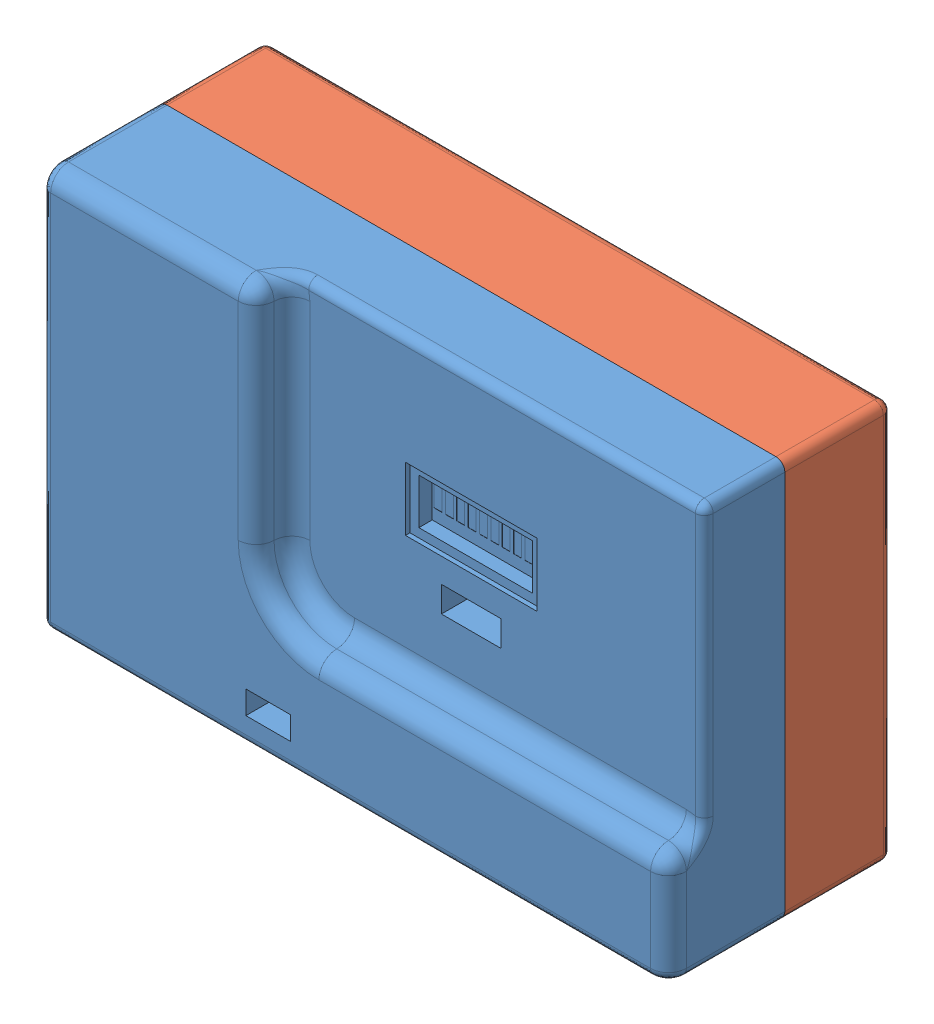
SolidWorks assembly Assem1, configuration Default. Lengths in mm.
Overall size (140.22 89.22 50.48).
7 component instances, 4 part files, 15 mates.
Components (placement in the parent):
- front part newest-1: front part newest [Default] at (-20.4572 26.9436 116.4245) size (140.22 89.22 26)
- Rear part-1: Rear part [Default] at (29.5428 67.4436 102.4245) x (1 0 0) z (0 1 0) size (140 26 89)
- 18650 battery holder-1: 18650 battery holder [Default] at (-4.2072 29.4436 101.3245) x (-1 0 0) z (0 0 -1) size (21.2 87 18.2)
- 18650 battery holder-2: 18650 battery holder [Default] at (18.2928 29.4436 101.3245) x (-1 0 0) z (0 0 -1) size (21.2 87 18.2)
- 18650 battery holder-3: 18650 battery holder [Default] at (40.7928 29.4436 101.3245) x (-1 0 0) z (0 0 -1) size (21.2 87 18.2)
- 18650 battery holder-4: 18650 battery holder [Default] at (63.2928 29.4436 101.3245) x (-1 0 0) z (0 0 -1) size (21.2 87 18.2)
- lid-1: lid [Default] at (29.414 67.7508 88.0876) x (1 0 0) z (0 0.999995 0.003206) size (97.6 8 85.9)
Mates (geometry in assembly coordinates):
- Coincident1: coincident aligned: line of front part newest-1 through (97.5428 111.9436 110.4245) axis (-1 0 0); line of Rear part-1 through (97.5428 111.9436 110.4245) axis (-1 0 0)
- Coincident3: coincident aligned: line of front part newest-1 through (99.5428 24.9436 110.4245) axis (0 1 0); line of Rear part-1 through (99.5428 24.9436 110.4245) axis (0 1 0)
- Coincident4: coincident anti-aligned: plane of Rear part-1 through (29.5428 67.4436 110.4245) normal (0 0 -1); plane of 18650 battery holder-1 through (-13.8172 30.4336 110.4245) normal (0 0 1)
- Concentric1: concentric aligned: circle of Rear part-1; circle of 18650 battery holder-1
- Parallel1: parallel anti-aligned: line of Rear part-1 through (74.5428 107.4436 110.4245) axis (0 -1 0); line of 18650 battery holder-1 through (6.3928 30.4436 109.4245) axis (0 1 0)
- Concentric2: concentric aligned: circle of Rear part-1; circle of 18650 battery holder-2
- Coincident6: coincident anti-aligned: plane of Rear part-1 through (29.5428 67.4436 110.4245) normal (0 0 -1); plane of 18650 battery holder-2 through (8.6828 30.4336 110.4245) normal (0 0 1)
- Parallel2: parallel anti-aligned: line of Rear part-1 through (74.5428 107.4436 110.4245) axis (0 -1 0); line of 18650 battery holder-2 through (28.8928 30.4436 109.4245) axis (0 1 0)
- Concentric3: concentric aligned: circle of Rear part-1; circle of 18650 battery holder-3
- Coincident8: coincident anti-aligned: plane of Rear part-1 through (29.5428 67.4436 110.4245) normal (0 0 -1); plane of 18650 battery holder-3 through (31.1828 30.4336 110.4245) normal (0 0 1)
- Parallel3: parallel anti-aligned: line of Rear part-1 through (74.5428 107.4436 110.4245) axis (0 -1 0); line of 18650 battery holder-3 through (51.3928 30.4436 109.4245) axis (0 1 0)
- Coincident11: coincident anti-aligned: plane of Rear part-1 through (29.5428 67.4436 110.4245) normal (0 0 -1); plane of 18650 battery holder-4 through (53.6828 30.4336 110.4245) normal (0 0 1)
- Concentric4: concentric aligned: circle of Rear part-1; circle of 18650 battery holder-4
- Parallel4: parallel anti-aligned: line of Rear part-1 through (74.5428 107.4436 110.4245) axis (0 -1 0); line of 18650 battery holder-4 through (73.8928 30.4436 109.4245) axis (0 1 0)
- Coincident17: coincident anti-aligned: line of Rear part-1 through (1.5428 110.4436 90.4245) axis (1 0 0); line of lid-1 through (6.9766 110.4436 90.4245) axis (-1 0 0)
